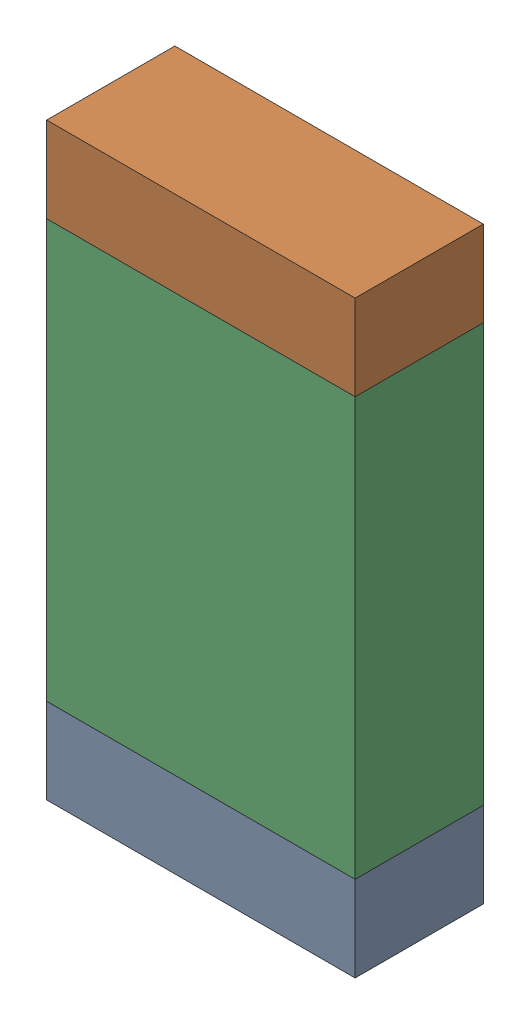
SolidWorks assembly R20, configuration Default. Lengths in mm.
Overall size (0.55 1.05 0.23).
6 component instances, 2 part files, 0 mates.
Components (placement in the parent):
- 822503136-1: 822503136 [Default] at (8.6867 13.7167 0.0254) size (0.55 0.15 0.23)
  - Extruded_13-1: Extruded_13 [Default] at origin size (0.55 0.15 0.23)
- 822503136-2: 822503136 [Default] at (8.6867 14.6143 0.0254) size (0.55 0.15 0.23)
  - Extruded_13-1: Extruded_13 [Default] at origin size (0.55 0.15 0.23)
- 822503272-1: 822503272 [Default] at (8.6867 14.1654 0.0254) size (0.55 0.75 0.23)
  - Extruded_14-1: Extruded_14 [Default] at origin size (0.55 0.75 0.23)
